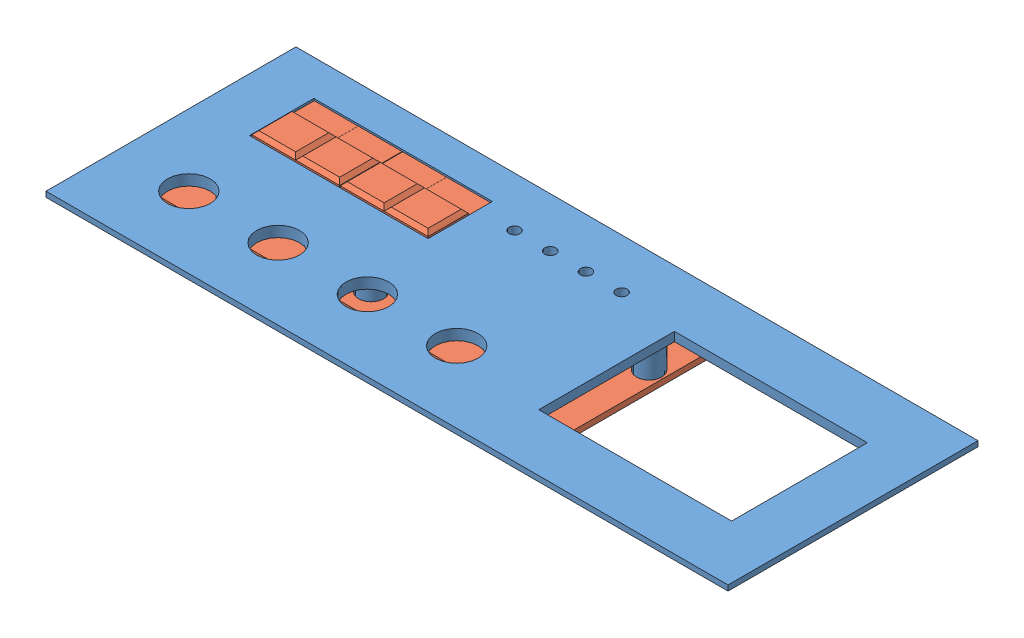
SolidWorks assembly front_panel_assy, configuration Default. Lengths in mm.
Overall size (191 15.9 70).
2 component instances, 2 part files, 3 mates.
Components (placement in the parent):
- front_3mm-1: front_3mm [Default] at (-75.2377 22.9171 25.8875) size (191 12.8 70)
- PCB-1: PCB [Default] at (-145.8385 11.5171 48.8584) x (1 0 0) z (0 1 0) size (116.97 41.28 15.9)
Mates (geometry in assembly coordinates):
- Coincident2: coincident anti-aligned: plane of front_3mm-1 through (-149.1754 25.9171 12.6505) normal (0 0 -1); plane of PCB-1 through (-123.7946 60.1075 12.6505) normal (0 0 1)
- Coincident3: coincident anti-aligned: plane of front_3mm-1 through (-99.1754 25.9171 -5.3495) normal (-1 0 0); plane of PCB-1 through (-99.1754 60.1075 -4.8496) normal (1 0 0)
- Coincident4: coincident aligned: plane of front_3mm-1 through (-75.2377 25.9171 25.8875) normal (0 1 0); plane of PCB-1 through (-145.8385 25.9171 48.8584) normal (0 1 0)
